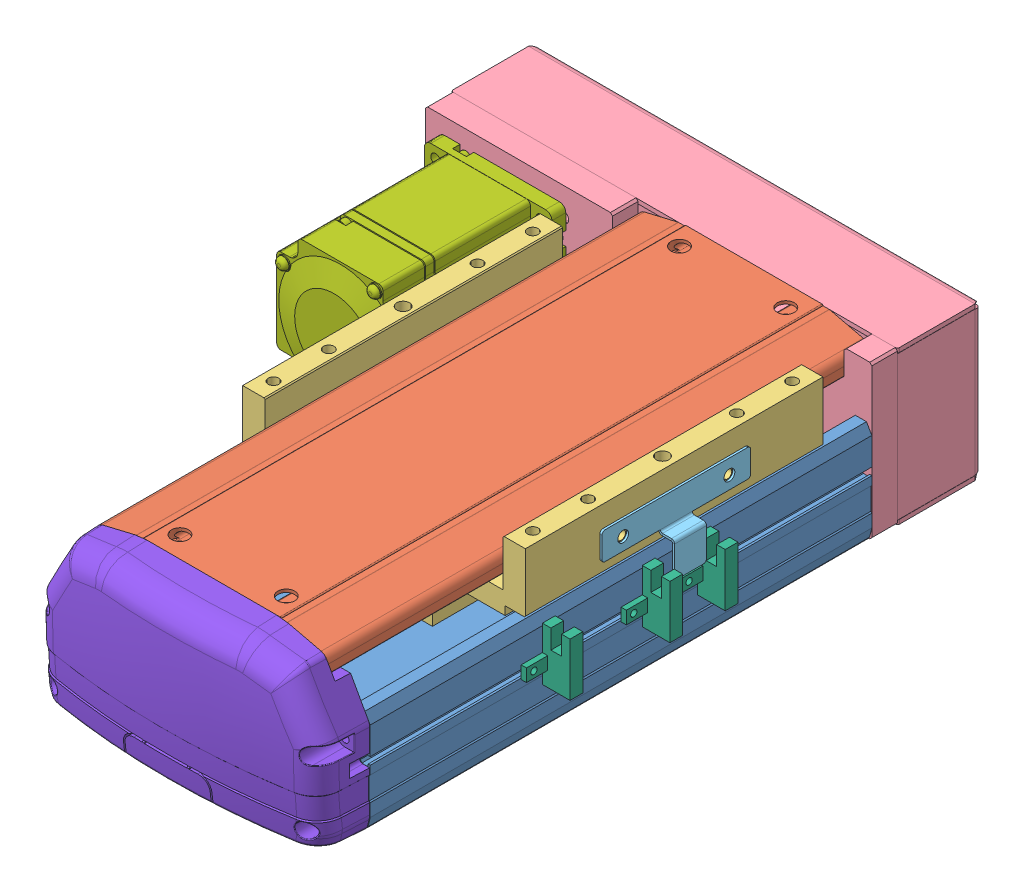
SolidWorks assembly S14-BL-200W, configuration 默认. Lengths in mm.
Overall size (223.28 78.03 318).
10 component instances, 8 part files, 29 mates.
Components (placement in the parent):
- S14-BM底座^S14-BL-200W-1: S14-BM底座^S14-BL-200W [默认] at origin size (135 48.03 259) (virtual)
- S14-BM上盖^S14-BL-200W-1: S14-BM上盖^S14-BL-200W [默认] at (0 61 -12) size (109 12.5 255) (virtual)
- S14-BR-SFSR16滑座^S14-BL-200W-1: S14-BR-SFSR16滑座^S14-BL-200W [默认] at (1.39 35.7784 112) x (-1 0 0) z (0 0 -1) size (133 62 140) (virtual)
- 复件 S14-BL电机板罩壳^S14-BL-200W-1: 复件 S14-BL电机板罩壳^S14-BL-200W [默认] at (34.6396 24.1 343.3649) x (1 0 0) z (0 1 0) size (210.56 52 72) (virtual)
- 复件 外置感应片ST14-17^S14-BL-200W-1: 复件 外置感应片ST14-17^S14-BL-200W [默认] at (67.4964 55 92) x (0 0 -1) z (1 0 0) size (70 30.4 7.7) (virtual)
- 复件 光电开关EE-SX672^S14-BL-200W-1: 复件 光电开关EE-SX672^S14-BL-200W [默认] at (67.5 19.7 82) x (0 0 -1) z (1 0 0) size (26 25 13) (virtual)
- 复件 光电开关EE-SX672^S14-BL-200W-2: 复件 光电开关EE-SX672^S14-BL-200W [默认] at (67.5 19.7 108) x (0 0 -1) z (1 0 0) size (26 25 13) (virtual)
- 复件 光电开关EE-SX672^S14-BL-200W-3: 复件 光电开关EE-SX672^S14-BL-200W [默认] at (67.5 19.7 155) x (0 0 -1) z (1 0 0) size (26 25 13) (virtual)
- 复件 (2) MSMD022P1AA_200W^S14-BL-200W-2: 复件 (2) MSMD022P1AA_200W^S14-BL-200W [默认] at (-106.5 35.4 0) x (0 0 -1) z (-1 0 0) size (109 60 60) (virtual)
- 复件 (2) 13-14塑胶端盖^S14-BL-200W-1: 复件 (2) 13-14塑胶端盖^S14-BL-200W [Default] at (0 1 256) x (-1 0 0) z (0 0 -1) size (134.5 73.26 30.08) (virtual)
Mates (geometry in assembly coordinates):
- 距离10: distance = 73.5 mm: plane of S14-BM上盖^S14-BL-200W-1 through (-32 73.5 243) normal (0 1 0); plane of S14-BM底座^S14-BL-200W-1 through (-65.3077 0 259) normal (0 -1 0)
- 距离17: distance = 1.39 mm: plane of S14-BR-SFSR16滑座^S14-BL-200W-1 through (1.39 35.7784 112) normal (-1 0 0); plane of S14-BM底座^S14-BL-200W-1 through (0 0 0) normal (1 0 0)
- 重合155: coincident: plane of S14-BM底座^S14-BL-200W-1 through (0 0 0) normal (1 0 0); plane of S14-BM上盖^S14-BL-200W-1 through (0 61 -12) normal (1 0 0)
- 距离12: distance = 78 mm: plane of S14-BR-SFSR16滑座^S14-BL-200W-1 through (-66.5036 78 162) normal (0 1 0); plane of S14-BM底座^S14-BL-200W-1 through (-65.3077 0 259) normal (0 -1 0)
- 重合180: coincident: plane of S14-BM底座^S14-BL-200W-1 through (0 0 0) normal (0 0 1); plane of assembly through (0 0 0) normal (0 0 1)
- 重合181: coincident: plane of S14-BM底座^S14-BL-200W-1 through (0 0 0) normal (0 1 0); plane of assembly through (0 0 0) normal (0 1 0)
- 重合182: coincident: plane of S14-BM底座^S14-BL-200W-1 through (0 0 0) normal (1 0 0); plane of assembly through (0 0 0) normal (1 0 0)
- 重合193: coincident: plane of S14-BM底座^S14-BL-200W-1 through (-56.75 26.5 0) normal (0 0 -1); plane of 复件 S14-BL电机板罩壳^S14-BL-200W-1 through (-37.5 37 0) normal (0 0 1)
- 距离25: distance = 1 mm: plane of 复件 S14-BL电机板罩壳^S14-BL-200W-1 through (67.5 1 -12) normal (0 -1 0); plane of S14-BM底座^S14-BL-200W-1 through (31 0 259) normal (0 -1 0)
- 重合195: coincident: plane of S14-BM底座^S14-BL-200W-1 through (67.5 12 259) normal (1 0 0); plane of 复件 S14-BL电机板罩壳^S14-BL-200W-1 through (67.5 1 -12) normal (1 0 0)
- 重合196: coincident: plane of S14-BM底座^S14-BL-200W-1 through (67.5 43.67 259) normal (1 0 0); plane of 复件 光电开关EE-SX672^S14-BL-200W-1 through (67.5 44.7 82) normal (-1 0 0)
- 距离26: distance = 76 mm: plane of 复件 光电开关EE-SX672^S14-BL-200W-1 through (80.5 19.7 76) normal (0 0 -1); plane of S14-BM底座^S14-BL-200W-1 through (-56.75 26.5 0) normal (0 0 -1)
- 距离27: distance = 19.7 mm: plane of 复件 光电开关EE-SX672^S14-BL-200W-1 through (80.5 19.7 82) normal (0 -1 0); plane of S14-BM底座^S14-BL-200W-1 through (31 0 259) normal (0 -1 0)
- 同心80: concentric: cylinder of S14-BR-SFSR16滑座^S14-BL-200W-1 through (66.9964 61 117) axis (1 0 0) radius 2.1; cylinder of 复件 外置感应片ST14-17^S14-BL-200W-1 through (67.4964 61 117) axis (1 0 0) radius 2.55
- 同心81: concentric: cylinder of S14-BR-SFSR16滑座^S14-BL-200W-1 through (66.9964 61 67) axis (1 0 0) radius 2.1; cylinder of 复件 外置感应片ST14-17^S14-BL-200W-1 through (67.4964 61 67) axis (1 0 0) radius 2.55
- 重合199: coincident: plane of S14-BR-SFSR16滑座^S14-BL-200W-1 through (66.4964 16 11.0287) normal (1 0 0); plane of 复件 外置感应片ST14-17^S14-BL-200W-1 through (66.4964 55 92) normal (-1 0 0)
- 重合200: coincident: plane of 复件 光电开关EE-SX672^S14-BL-200W-1 through (80.5 44.7 82) normal (1 0 0); plane of 复件 光电开关EE-SX672^S14-BL-200W-2 through (80.5 44.7 108) normal (1 0 0)
- 重合201: coincident: plane of 复件 光电开关EE-SX672^S14-BL-200W-1 through (80.5 19.7 82) normal (0 -1 0); plane of 复件 光电开关EE-SX672^S14-BL-200W-2 through (80.5 19.7 108) normal (0 -1 0)
- 重合202: coincident: plane of 复件 光电开关EE-SX672^S14-BL-200W-1 through (70 32.7 92) normal (0 0 1); plane of 复件 光电开关EE-SX672^S14-BL-200W-2 through (70 32.7 92) normal (0 0 -1)
- 重合203: coincident: plane of 复件 光电开关EE-SX672^S14-BL-200W-2 through (80.5 44.7 108) normal (1 0 0); plane of 复件 光电开关EE-SX672^S14-BL-200W-3 through (80.5 44.7 155) normal (1 0 0)
- 重合204: coincident: plane of 复件 光电开关EE-SX672^S14-BL-200W-2 through (80.5 19.7 108) normal (0 -1 0); plane of 复件 光电开关EE-SX672^S14-BL-200W-3 through (80.5 19.7 155) normal (0 -1 0)
- 距离28: distance = 81 mm: plane of 复件 光电开关EE-SX672^S14-BL-200W-3 through (80.5 19.7 155) normal (0 0 1); plane of S14-BM底座^S14-BL-200W-1 through (100.8342 -10 236) normal (0 0 1)
- 宽度1: width: plane of 复件 外置感应片ST14-17^S14-BL-200W-1 through (74.1964 37.6 99.5) normal (0 0 1); plane of 复件 外置感应片ST14-17^S14-BL-200W-1 through (74.1964 53 84.5) normal (0 0 -1); plane of 复件 光电开关EE-SX672^S14-BL-200W-2 through (80.5 19.7 102) normal (0 0 -1); plane of 复件 光电开关EE-SX672^S14-BL-200W-1 through (80.5 19.7 82) normal (0 0 1)
- 同心82: concentric: cylinder of S14-BM底座^S14-BL-200W-1 through (62.5 39.5 259) axis (0 0 -1) radius 1.4777; cylinder of 复件 (2) 13-14塑胶端盖^S14-BL-200W-1 through (62.5 39.5 236) axis (0 0 -1) radius 2.1
- 宽度3: width: plane of S14-BM底座^S14-BL-200W-1 through (-67.5 12 259) normal (-1 0 0); plane of S14-BM底座^S14-BL-200W-1 through (67.5 12 259) normal (1 0 0); plane of 复件 (2) 13-14塑胶端盖^S14-BL-200W-1 through (67.25 46.7626 236) normal (0.999048 0 0.043619); plane of 复件 (2) 13-14塑胶端盖^S14-BL-200W-1 through (-67.25 2.8914 236) normal (-0.999048 0 0.043619)
- 重合209: coincident: plane of S14-BM底座^S14-BL-200W-1 through (-100.8342 -10 236) normal (0 0 1); plane of 复件 (2) 13-14塑胶端盖^S14-BL-200W-1 through (0 1 236) normal (0 0 -1)
- 宽度4: width: plane of 复件 S14-BL电机板罩壳^S14-BL-200W-1 through (-103.5 60.4 0) normal (0 -1 0); plane of 复件 S14-BL电机板罩壳^S14-BL-200W-1 through (-103.5 10.4 0) normal (0 1 0); cylinder of 复件 (2) MSMD022P1AA_200W^S14-BL-200W-2 through (-106.5 35.4 -14.75) axis (0 0 -1) radius 5.5
- 重合210: coincident: plane of 复件 S14-BL电机板罩壳^S14-BL-200W-1 through (-37.5 37 0) normal (0 0 1); plane of 复件 (2) MSMD022P1AA_200W^S14-BL-200W-2 through (-106.5 35.4 0) normal (0 0 -1)
- 距离30: distance = 30 mm: moEndPointRef_w of 复件 S14-BL电机板罩壳^S14-BL-200W-1; plane of 复件 (2) MSMD022P1AA_200W^S14-BL-200W-2 through (-136.5 62.4 6.5) normal (-1 0 0)
